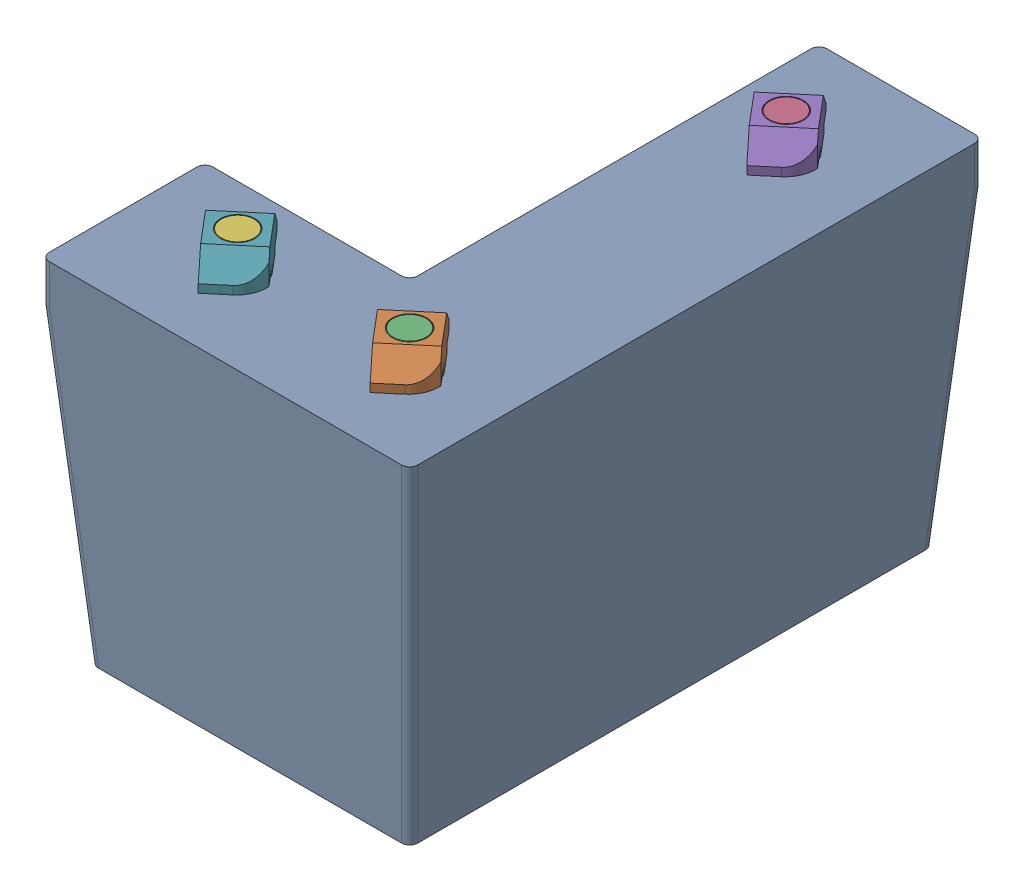
SolidWorks assembly back_right_foot, configuration Default. Lengths in mm.
Overall size (45 45 70).
7 component instances, 3 part files, 0 mates.
Components (placement in the parent):
- budget_foot_Back Right Foot-1: budget_foot_Back Right Foot [Default] at (477.3115 276.9149 195.384) x (0 0 -1) z (1 0 0) size (70 40 45)
- m5_locking_t_nut_20x20_generic-1: m5_locking_t_nut_20x20_generic [Default] at (469.6039 281.9149 183.4489) x (-0.645039 0 -0.76415) z (-0.76415 0 0.645039) size (10 4.5 6)
- m5_low_profile_screw_template_M5 x 10-1: m5_low_profile_screw_template_M5 x 10 [Default] at (467.3115 281.9149 185.384) x (0 1 0) z (-0.452256 0 0.891888) size (11.62 9 9)
- m5_low_profile_screw_template_M5 x 10-2: m5_low_profile_screw_template_M5 x 10 [Default] at (467.3115 281.9149 139.384) x (0 1 0) z (-0.452256 0 0.891888) size (11.62 9 9)
- m5_locking_t_nut_20x20_generic-2: m5_locking_t_nut_20x20_generic [Default] at (469.6039 281.9149 137.4489) x (-0.645039 0 -0.76415) z (-0.76415 0 0.645039) size (10 4.5 6)
- m5_low_profile_screw_template_M5 x 10-3: m5_low_profile_screw_template_M5 x 10 [Default] at (446.3115 281.9149 185.384) x (0 1 0) z (-0.452256 0 0.891888) size (11.62 9 9)
- m5_locking_t_nut_20x20_generic-3: m5_locking_t_nut_20x20_generic [Default] at (448.6039 281.9149 183.4489) x (-0.645039 0 -0.76415) z (-0.76415 0 0.645039) size (10 4.5 6)
